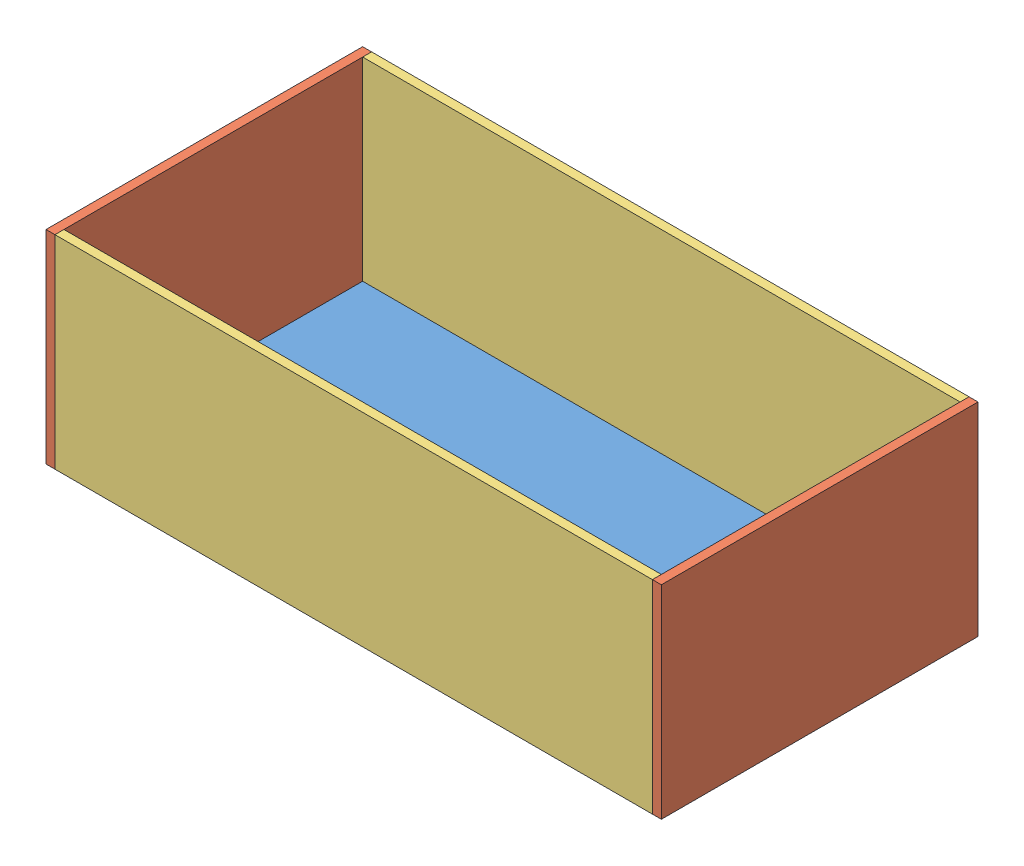
SolidWorks assembly Speaker Box, configuration Default. Lengths in mm.
Overall size (261.62 86.36 134.62).
6 component instances, 4 part files, 15 mates.
Components (placement in the parent):
- Back plate-1: Back plate [Default] at (-4507.4049 137.3027 2520.5373) size (254 3.81 127)
- Front plate-1: Front plate [Default] at (141.8951 217.3127 182.8434) size (254 6.35 127) (hidden)
- Side-1: Side [Default] at (-50.9292 -667.6417 3044.0565) x (0 0 -1) z (0 -1 0) size (134.62 3.81 86.36)
- Side-2: Side [Default] at (210.6908 -667.6417 -2647.4105) x (0 0 1) z (0 -1 0) size (134.62 3.81 86.36)
- Top-1: Top [Default] at (75.9645 198.2851 134.823) x (1 0 0) z (0 1 0) size (254 3.81 86.36)
- Top-2: Top [Default] at (75.9645 198.2851 265.633) x (1 0 0) z (0 1 0) size (254 3.81 86.36)
Mates (geometry in assembly coordinates):
- Coincident18: coincident anti-aligned: plane of Side-2 through (206.8808 -667.6417 -2647.4105) normal (-1 0 0); plane of Top-1 through (206.8808 137.3027 131.013) normal (1 0 0)
- Coincident19: coincident aligned: plane of Side-2 through (206.8808 223.6627 131.013) normal (0 0 -1); plane of Top-1 through (75.9645 198.2851 131.013) normal (0 0 -1)
- Coincident20: coincident anti-aligned: plane of Side-2 through (206.8808 -667.6417 -2647.4105) normal (-1 0 0); plane of Top-2 through (206.8808 137.3027 261.823) normal (1 0 0)
- Coincident22: coincident anti-aligned: plane of Side-1 through (-47.1192 -655.5062 3044.0565) normal (1 0 0); plane of Top-2 through (-47.1192 137.3027 261.823) normal (-1 0 0)
- Coincident25: coincident anti-aligned: plane of Front plate-1 through (-47.1192 223.6627 134.823) normal (0 0 -1); plane of Top-1 through (75.9645 198.2851 134.823) normal (0 0 1)
- Coincident26: coincident anti-aligned: plane of Front plate-1 through (-47.1192 223.6627 134.823) normal (-1 0 0); plane of Side-1 through (-47.1192 -655.5062 3044.0565) normal (1 0 0)
- Coincident27: coincident aligned: plane of Front plate-1 through (141.8951 223.6627 182.8434) normal (0 1 0); plane of Top-1 through (-47.1192 223.6627 131.013) normal (0 1 0)
- Coincident29: coincident aligned: plane of Front plate-1 through (141.8951 223.6627 182.8434) normal (0 1 0); plane of Side-2 through (206.8808 223.6627 131.013) normal (0 1 0)
- Coincident30: coincident anti-aligned: plane of Back plate-1 through (206.8808 141.1127 134.823) normal (1 0 0); plane of Side-2 through (206.8808 -667.6417 -2647.4105) normal (-1 0 0)
- Coincident31: coincident anti-aligned: plane of Back plate-1 through (-47.1192 141.1127 134.823) normal (0 0 -1); plane of Top-1 through (75.9645 198.2851 134.823) normal (0 0 1)
- Coincident32: coincident aligned: plane of Back plate-1 through (-4507.4049 137.3027 2520.5373) normal (0 -1 0); plane of Top-1 through (-47.1192 137.3027 131.013) normal (0 -1 0)
- Coincident34: coincident anti-aligned: plane of Front plate-1 through (-47.1192 223.6627 261.823) normal (0 0 1); plane of Top-2 through (75.9645 198.2851 261.823) normal (0 0 -1)
- Coincident35: coincident aligned: plane of Front plate-1 through (141.8951 223.6627 182.8434) normal (0 1 0); plane of Top-2 through (-47.1192 223.6627 261.823) normal (0 1 0)
- Coincident36: coincident aligned: plane of Side-1 through (-47.1192 235.7982 265.633) normal (0 0 1); plane of Top-2 through (75.9645 198.2851 265.633) normal (0 0 1)
- Coincident37: coincident aligned: plane of Front plate-1 through (141.8951 223.6627 182.8434) normal (0 1 0); plane of Side-1 through (-47.1192 223.6627 265.633) normal (0 1 0)
